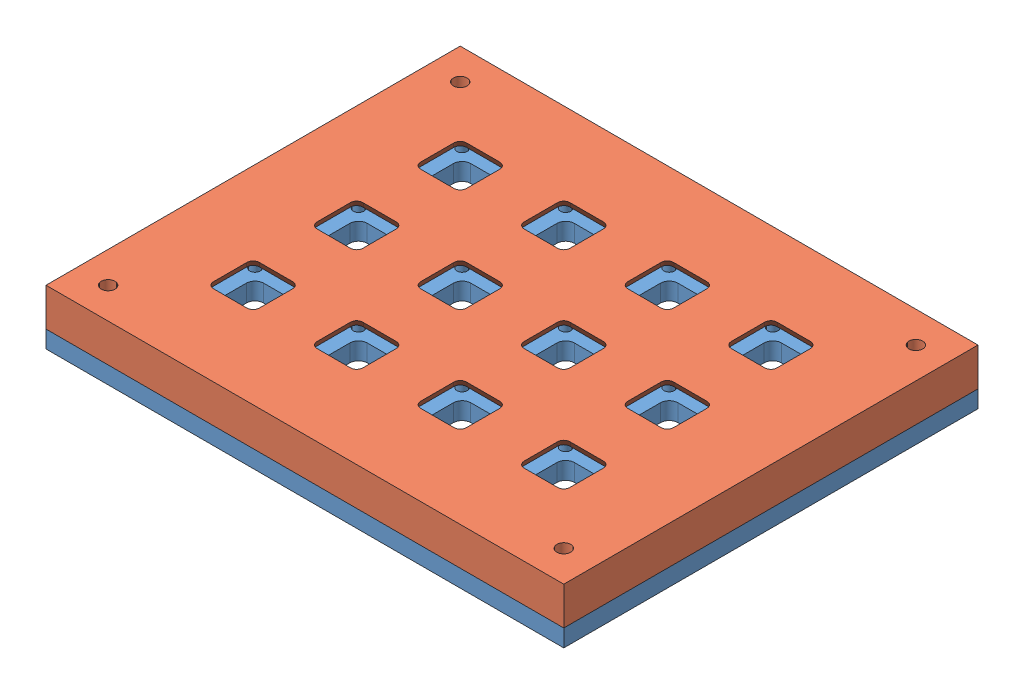
SolidWorks assembly Assem1, configuration Default. Lengths in mm.
Overall size (76.2 8.13 60.96).
2 component instances, 2 part files, 3 mates.
Components (placement in the parent):
- bottom_plate-1: bottom_plate [Default] at (21.7348 39.1897 60.8681) size (76.2 4.57 60.96)
- top_plate-1: top_plate [Default] at (21.7348 47.3177 60.8681) x (-1 0 0) z (0 0 1) size (76.2 5.59 60.96)
Mates (geometry in assembly coordinates):
- Coincident1: coincident: plane of bottom_plate-1 through (21.7348 41.7297 60.8681) normal (0 1 0); plane of top_plate-1 through (21.7348 41.7297 60.8681) normal (0 -1 0)
- Concentric1: concentric: circle of bottom_plate-1; circle of top_plate-1
- Concentric2: concentric anti-aligned: circle of bottom_plate-1; circle of top_plate-1
